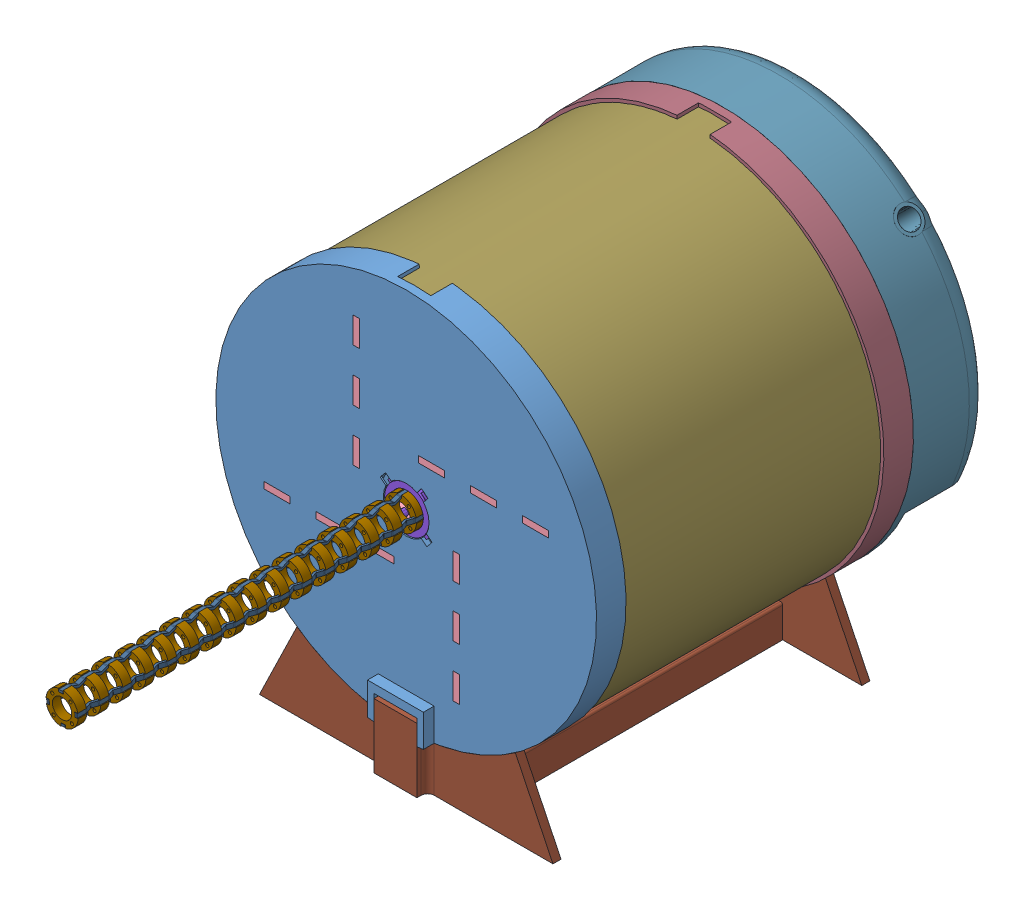
SolidWorks assembly Endo-Continuum-Robot, configuration Default. Lengths in mm.
Overall size (199.74 208.48 344.52).
87 component instances, 16 part files, 24 mates.
Components (placement in the parent):
- FrontCover-1: FrontCover [Default] at (-10.0743 108.611 457.4034) x (0 -1 0) z (0 0 1) size (177.22 177.22 18.75)
- ServoSet-1: ServoSet [Default] at (-169.2832 140.7245 631.1667) x (0 1 0) z (0 0 -1) size (82.84 52.3 148.09)
  - MG996R-Servo-with-Hub-1: MG996R-Servo-with-Hub [Default] at (-42.4416 98.8668 240.9659) x (0 0 -1) z (1 0 0) size (24.11 48.3 54.1)
    - MG996R-Servo-1: MG996R-Servo [Default] at (29.3026 10.0421 49.0781) size (20.3 45.5 54.1)
    - Servo-Hub-1: Servo-Hub [Default] at (29.3026 56.1421 60.3281) x (0.973354 0 0.229307) z (-0.229307 0 0.973354) size (20.05 5.6 20.05)
  - ServoHolderDirect-2: ServoHolderDirect [Default] at (3.7865 137.5089 247.5133) x (-1 0 0) z (0 0 1) size (72.5 3 147.5)
  - MG996R-Servo-with-Hub-4: MG996R-Servo-with-Hub [Default] at (64.7146 98.8668 238.0606) x (0 0 1) z (-1 0 0) size (24.11 48.3 54.1)
    - MG996R-Servo-1: MG996R-Servo [Default] at (29.3026 10.0421 49.0781) size (20.3 45.5 54.1)
    - Servo-Hub-1: Servo-Hub [Default] at (29.3026 56.1421 60.3281) x (0.973354 0 0.229307) z (-0.229307 0 0.973354) size (20.05 5.6 20.05)
  - MG996R-Servo-with-Hub-5: MG996R-Servo-with-Hub [Default] at (53.0146 98.8668 274.0606) x (0 0 1) z (-1 0 0) size (24.11 48.3 54.1)
    - MG996R-Servo-1: MG996R-Servo [Default] at (29.3026 10.0421 49.0781) size (20.3 45.5 54.1)
    - Servo-Hub-1: Servo-Hub [Default] at (29.3026 56.1421 60.3281) x (0.973354 0 0.229307) z (-0.229307 0 0.973354) size (20.05 5.6 20.05)
  - MotorTransmissionMedium-1: MotorTransmissionMedium [Default] at (4.3865 154.2089 267.3633) x (0.973354 0 0.229307) z (0.229307 0 -0.973354) size (44 4 44)
  - MotorTransmissionSmall-1: MotorTransmissionSmall [Default] at (-7.3135 154.2089 303.3633) x (0.973354 0 0.229307) z (0.229307 0 -0.973354) size (24 4 24)
  - MotorTransmissionLarge-1: MotorTransmissionLarge [Default] at (17.8865 154.2089 211.6633) x (-0.973354 0 -0.229307) z (-0.229307 0 0.973354) size (64 4 64)
- ServoSet-3: ServoSet [Default] at (-42.1878 -50.5979 631.1667) x (-1 0 0) z (0 0 -1) size (82.84 52.3 148.09)
  - MG996R-Servo-with-Hub-1: MG996R-Servo-with-Hub [Default] at (-42.4416 98.8668 240.9659) x (0 0 -1) z (1 0 0) size (24.11 48.3 54.1)
    - MG996R-Servo-1: MG996R-Servo [Default] at (29.3026 10.0421 49.0781) size (20.3 45.5 54.1)
    - Servo-Hub-1: Servo-Hub [Default] at (29.3026 56.1421 60.3281) x (0.973354 0 0.229307) z (-0.229307 0 0.973354) size (20.05 5.6 20.05)
  - ServoHolderDirect-2: ServoHolderDirect [Default] at (3.7865 137.5089 247.5133) x (-1 0 0) z (0 0 1) size (72.5 3 147.5)
  - MG996R-Servo-with-Hub-4: MG996R-Servo-with-Hub [Default] at (64.7146 98.8668 238.0606) x (0 0 1) z (-1 0 0) size (24.11 48.3 54.1)
    - MG996R-Servo-1: MG996R-Servo [Default] at (29.3026 10.0421 49.0781) size (20.3 45.5 54.1)
    - Servo-Hub-1: Servo-Hub [Default] at (29.3026 56.1421 60.3281) x (0.973354 0 0.229307) z (-0.229307 0 0.973354) size (20.05 5.6 20.05)
  - MG996R-Servo-with-Hub-5: MG996R-Servo-with-Hub [Default] at (53.0146 98.8668 274.0606) x (0 0 1) z (-1 0 0) size (24.11 48.3 54.1)
    - MG996R-Servo-1: MG996R-Servo [Default] at (29.3026 10.0421 49.0781) size (20.3 45.5 54.1)
    - Servo-Hub-1: Servo-Hub [Default] at (29.3026 56.1421 60.3281) x (0.973354 0 0.229307) z (-0.229307 0 0.973354) size (20.05 5.6 20.05)
  - MotorTransmissionMedium-1: MotorTransmissionMedium [Default] at (4.3865 154.2089 267.3633) x (0.973354 0 0.229307) z (0.229307 0 -0.973354) size (44 4 44)
  - MotorTransmissionSmall-1: MotorTransmissionSmall [Default] at (-7.3135 154.2089 303.3633) x (0.973354 0 0.229307) z (0.229307 0 -0.973354) size (24 4 24)
  - MotorTransmissionLarge-1: MotorTransmissionLarge [Default] at (17.8865 154.2089 211.6633) x (-0.973354 0 -0.229307) z (-0.229307 0 0.973354) size (64 4 64)
- ServoSet-4: ServoSet [Default] at (149.1345 76.4975 631.1667) x (0 -1 0) z (0 0 -1) size (82.84 52.3 148.09)
  - MG996R-Servo-with-Hub-1: MG996R-Servo-with-Hub [Default] at (-42.4416 98.8668 240.9659) x (0 0 -1) z (1 0 0) size (24.11 48.3 54.1)
    - MG996R-Servo-1: MG996R-Servo [Default] at (29.3026 10.0421 49.0781) size (20.3 45.5 54.1)
    - Servo-Hub-1: Servo-Hub [Default] at (29.3026 56.1421 60.3281) x (0.973354 0 0.229307) z (-0.229307 0 0.973354) size (20.05 5.6 20.05)
  - ServoHolderDirect-2: ServoHolderDirect [Default] at (3.7865 137.5089 247.5133) x (-1 0 0) z (0 0 1) size (72.5 3 147.5)
  - MG996R-Servo-with-Hub-4: MG996R-Servo-with-Hub [Default] at (64.7146 98.8668 238.0606) x (0 0 1) z (-1 0 0) size (24.11 48.3 54.1)
    - MG996R-Servo-1: MG996R-Servo [Default] at (29.3026 10.0421 49.0781) size (20.3 45.5 54.1)
    - Servo-Hub-1: Servo-Hub [Default] at (29.3026 56.1421 60.3281) x (0.973354 0 0.229307) z (-0.229307 0 0.973354) size (20.05 5.6 20.05)
  - MG996R-Servo-with-Hub-5: MG996R-Servo-with-Hub [Default] at (53.0146 98.8668 274.0606) x (0 0 1) z (-1 0 0) size (24.11 48.3 54.1)
    - MG996R-Servo-1: MG996R-Servo [Default] at (29.3026 10.0421 49.0781) size (20.3 45.5 54.1)
    - Servo-Hub-1: Servo-Hub [Default] at (29.3026 56.1421 60.3281) x (0.973354 0 0.229307) z (-0.229307 0 0.973354) size (20.05 5.6 20.05)
  - MotorTransmissionMedium-1: MotorTransmissionMedium [Default] at (4.3865 154.2089 267.3633) x (0.973354 0 0.229307) z (0.229307 0 -0.973354) size (44 4 44)
  - MotorTransmissionSmall-1: MotorTransmissionSmall [Default] at (-7.3135 154.2089 303.3633) x (0.973354 0 0.229307) z (0.229307 0 -0.973354) size (24 4 24)
  - MotorTransmissionLarge-1: MotorTransmissionLarge [Default] at (17.8865 154.2089 211.6633) x (-0.973354 0 -0.229307) z (-0.229307 0 0.973354) size (64 4 64)
- ServoSet-5: ServoSet [Default] at (22.0392 267.8199 631.1667) x (1 0 0) z (0 0 -1) size (82.84 52.3 148.09)
  - MG996R-Servo-with-Hub-1: MG996R-Servo-with-Hub [Default] at (-42.4416 98.8668 240.9659) x (0 0 -1) z (1 0 0) size (24.11 48.3 54.1)
    - MG996R-Servo-1: MG996R-Servo [Default] at (29.3026 10.0421 49.0781) size (20.3 45.5 54.1)
    - Servo-Hub-1: Servo-Hub [Default] at (29.3026 56.1421 60.3281) x (0.973354 0 0.229307) z (-0.229307 0 0.973354) size (20.05 5.6 20.05)
  - ServoHolderDirect-2: ServoHolderDirect [Default] at (3.7865 137.5089 247.5133) x (-1 0 0) z (0 0 1) size (72.5 3 147.5)
  - MG996R-Servo-with-Hub-4: MG996R-Servo-with-Hub [Default] at (64.7146 98.8668 238.0606) x (0 0 1) z (-1 0 0) size (24.11 48.3 54.1)
    - MG996R-Servo-1: MG996R-Servo [Default] at (29.3026 10.0421 49.0781) size (20.3 45.5 54.1)
    - Servo-Hub-1: Servo-Hub [Default] at (29.3026 56.1421 60.3281) x (0.973354 0 0.229307) z (-0.229307 0 0.973354) size (20.05 5.6 20.05)
  - MG996R-Servo-with-Hub-5: MG996R-Servo-with-Hub [Default] at (53.0146 98.8668 274.0606) x (0 0 1) z (-1 0 0) size (24.11 48.3 54.1)
    - MG996R-Servo-1: MG996R-Servo [Default] at (29.3026 10.0421 49.0781) size (20.3 45.5 54.1)
    - Servo-Hub-1: Servo-Hub [Default] at (29.3026 56.1421 60.3281) x (0.973354 0 0.229307) z (-0.229307 0 0.973354) size (20.05 5.6 20.05)
  - MotorTransmissionMedium-1: MotorTransmissionMedium [Default] at (4.3865 154.2089 267.3633) x (0.973354 0 0.229307) z (0.229307 0 -0.973354) size (44 4 44)
  - MotorTransmissionSmall-1: MotorTransmissionSmall [Default] at (-7.3135 154.2089 303.3633) x (0.973354 0 0.229307) z (0.229307 0 -0.973354) size (24 4 24)
  - MotorTransmissionLarge-1: MotorTransmissionLarge [Default] at (17.8865 154.2089 211.6633) x (-0.973354 0 -0.229307) z (-0.229307 0 0.973354) size (64 4 64)
- SpineAndLock-1: SpineAndLock [Default] at (8.3738 114.3681 430.6531) x (-0.760407 0.649447 0) z (0 0 1) size (23.7 23.7 163.57)
  - SpineTwistLock-1: SpineTwistLock [Default] at (10.2892 -83.6412 26.4253) size (23.7 23.7 3)
  - Spine3Segments-1: Spine3Segments [Default] at (4.5097 28.4554 36.373) x (-0.707107 -0.707107 0) z (0.707107 -0.707107 0) size (14.85 161.57 14.85)
    - RigidDisc-1: RigidDisc [Default] at (4.4669 6.9477 12.6403) size (14.85 4 14.85)
    - RigidDisc-2: RigidDisc [Default] at (4.4669 -3.5523 12.6403) size (14.85 4 14.85)
    - RigidDisc-3: RigidDisc [Default] at (4.4669 -14.0523 12.6403) size (14.85 4 14.85)
    - RigidDisc-4: RigidDisc [Default] at (4.4669 -24.5523 12.6403) size (14.85 4 14.85)
    - RigidDisc-5: RigidDisc [Default] at (4.4669 -35.0523 12.6403) size (14.85 4 14.85)
    - Ligament-9: Ligament [Default] at (11.0169 10.9477 11.6403) x (0 -1 0) z (-1 0 0) size (161.57 2 2.03)
    - RigidDisc-16: RigidDisc [Default] at (4.4669 -45.5523 12.6403) size (14.85 4 14.85)
    - RigidDisc-17: RigidDisc [Default] at (4.4669 -56.0523 12.6403) size (14.85 4 14.85)
    - RigidDisc-18: RigidDisc [Default] at (4.4669 -66.5523 12.6403) size (14.85 4 14.85)
    - RigidDisc-19: RigidDisc [Default] at (4.4669 -77.0523 12.6403) size (14.85 4 14.85)
    - RigidDisc-20: RigidDisc [Default] at (4.4669 -87.5523 12.6403) size (14.85 4 14.85)
    - RigidDisc-21: RigidDisc [Default] at (4.4669 -98.0523 12.6403) size (14.85 4 14.85)
    - RigidDisc-22: RigidDisc [Default] at (4.4669 -108.5523 12.6403) size (14.85 4 14.85)
    - RigidDisc-23: RigidDisc [Default] at (4.4669 -119.0523 12.6403) size (14.85 4 14.85)
    - RigidDisc-24: RigidDisc [Default] at (4.4669 -129.5523 12.6403) size (14.85 4 14.85)
    - RigidDisc-25: RigidDisc [Default] at (4.4669 -140.0523 12.6403) size (14.85 4 14.85)
    - RigidDisc-26: RigidDisc [Default] at (4.4669 -150.5523 12.6403) size (14.85 4 14.85)
    - Ligament-11: Ligament [Default] at (3.4669 10.9477 6.0903) x (0 -1 0) z (0 0 1) size (161.57 2 2.03)
    - Ligament-12: Ligament [Default] at (-2.0831 10.9477 13.6403) x (0 -1 0) z (1 0 0) size (161.57 2 2.03)
    - Ligament-13: Ligament [Default] at (5.4669 10.9477 19.1903) x (0 -1 0) z (0 0 -1) size (161.57 2 2.03)
- BaseHolder-1: BaseHolder [Default] at (-10.0743 108.611 455.5284) x (0 1 0) z (0 0 -1) size (197.22 177.22 157.5)
- HubCover-1: HubCover [Default] at (-10.0743 108.611 313.6534) x (0.987237 -0.15926 0) z (0 0 1) size (174.22 174.22 140)
- MountAndBack-1: MountAndBack [Default] at (-138.6215 168.0928 198.6011) x (0 -1 0) z (0 0 1) size (177.22 177.22 50.53)
  - BackCover-1: BackCover [Default] at (59.4818 128.5471 115.0523) size (177.22 177.22 18.75)
  - URVMount-1: URVMount [Default] at (59.4818 128.5471 111.3023) x (0 -1 0) z (0 0 1) size (177.22 177.22 36.78)
  - Servo-Driver-1: Servo-Driver [Default] at (43.0849 82.2579 106.3023) x (0 0 1) z (-1 0 0) size (2 25 62.1)
  - Arduino-Uno-1: Arduino-Uno [Default] at (54.6997 184.2196 96.9884) x (0 1 0) z (0 0 -1) size (54 75 15)
Mates (geometry in assembly coordinates):
- Concentric1: concentric aligned: cylinder of FrontCover-1 through (-10.0743 108.611 453.6534) axis (0 0 1) radius 10.65; cylinder of SpineAndLock-1/SpineTwistLock-1 through (-10.0743 108.611 454.0784) axis (0 0 1) radius 10.35
- Concentric2: concentric anti-aligned: cylinder of FrontCover-1 through (-10.0743 108.611 457.4034) axis (0 0 -1) radius 88.611; cylinder of BackHubDirect-1 through (0 106.546 -147.5) axis (0 0 1) radius 88.611
- Concentric13: concentric anti-aligned: cylinder of FrontCover-1 through (-10.0743 108.611 457.4034) axis (0 0 -1) radius 88.611; cylinder of BaseHolder-1 through (-10.0743 108.611 453.6534) axis (0 0 1) radius 88.611
- Coincident16: coincident aligned: plane of FrontCover-1 through (-10.0743 108.611 457.4034) normal (0 0 1); plane of BaseHolder-1 through (-10.0743 108.611 457.4034) normal (0 0 1)
- Parallel1: parallel aligned: plane of FrontCover-1 through (-10.0743 174.761 447.4034) normal (0 -1 0); plane of BaseHolder-1 through (-78.3995 0 453.6534) normal (0 -1 0)
- Tangent2: tangent anti-aligned: face of BackHubDirect-1; plane of BackHubDirect-1 through (56 136.046 -160.5) normal (0 0 -1)
- Coincident17: coincident anti-aligned: plane of BackHubDirect-1 through (0 106.546 -150.5) normal (0 0 -1); plane of ServoDriverDirect-1 through (-35.2892 152.4928 -150.5) normal (0 0 1)
- Concentric16: concentric anti-aligned: cylinder of BackHubDirect-1 through (0 106.546 -147.5) axis (0 0 1) radius 88.611; cylinder of HubCover-1 through (-10.0743 108.611 453.6534) axis (0 0 -1) radius 87.111
- Coincident18: coincident anti-aligned: plane of FrontCover-1 through (-10.0743 108.611 453.6534) normal (0 0 -1); circle of HubCover-1
- Coincident19: coincident anti-aligned: plane of FrontCover-1 through (-31.7743 114.261 447.4034) normal (0 1 0); plane of ServoSet-1/ServoHolderDirect-2 through (-34.7743 114.261 383.6534) normal (0 -1 0)
- Coincident20: coincident anti-aligned: plane of FrontCover-1 through (-31.7743 114.261 447.4034) normal (-1 0 0); plane of ServoSet-1/ServoHolderDirect-2 through (-31.7743 144.511 383.6534) normal (1 0 0)
- Coincident21: coincident aligned: plane of FrontCover-1 through (-10.0743 108.611 457.4034) normal (0 0 1); plane of ServoSet-1/ServoHolderDirect-2 through (-34.7743 144.511 457.4034) normal (0 0 1)
- Coincident22: coincident aligned: plane of ServoSet-1/ServoHolderDirect-2 through (-34.7743 144.511 309.9034) normal (0 0 -1); plane of BackHubDirect-1 through (0 106.546 -147.5) normal (0 0 -1)
- Coincident23: coincident anti-aligned: plane of ServoSet-1/ServoHolderDirect-2 through (-34.7743 144.511 383.6534) normal (-1 0 0); plane of BackHubDirect-1 through (-24.7 106.546 -153.75) normal (1 0 0)
- Tangent7: tangent anti-aligned: cylinder of ? through (56 136.046 -160.5) axis (0 0 1) radius 1.5; edge_curve of ?
- Tangent8: tangent anti-aligned: cylinder of ? through (25 136.046 -160.5) axis (0 0 1) radius 1.5; edge_curve of ?
- Concentric17: concentric anti-aligned: cylinder of BackHubDirect-1 through (-36.3499 151.4322 -150.5) axis (0 0 1) radius 0.75; cylinder of ServoDriverDirect-1 through (-36.3499 151.4322 -150.5) axis (0 0 -1) radius 1
- Concentric18: concentric anti-aligned: cylinder of BackHubDirect-1 through (-56.2286 151.4322 -150.5) axis (0 0 1) radius 0.75; cylinder of ServoDriverDirect-1 through (-56.2286 151.4322 -150.5) axis (0 0 -1) radius 1
- Coincident24: coincident anti-aligned: plane of BaseHolder-1 through (-78.3995 0 453.6534) normal (0 -1 0)
- Concentric19: concentric anti-aligned: cylinder of FrontCover-1 through (-10.0743 108.611 457.4034) axis (0 0 -1) radius 88.611; cylinder of MountAndBack-1/BackCover-1 through (-10.0743 108.611 309.9034) axis (0 0 1) radius 88.611
- Coincident27: coincident aligned: plane of FrontCover-1 through (-2.3514 196.8848 443.6534) normal (-0.996195 0.087156 0); plane of MountAndBack-1/BackCover-1 through (-2.3514 196.8848 323.6534) normal (-0.996195 0.087156 0)
- Coincident28: coincident aligned: plane of ServoSet-1/ServoHolderDirect-2 through (-34.7743 144.511 309.9034) normal (0 0 -1); plane of MountAndBack-1/BackCover-1 through (-10.0743 108.611 309.9034) normal (0 0 -1)
- Concentric20: concentric aligned: cylinder of FrontCover-1 through (-10.0743 108.611 457.4034) axis (0 0 -1) radius 88.611; cylinder of HubCover-1 through (-10.0743 108.611 453.6534) axis (0 0 -1) radius 87.111
- Coincident29: coincident anti-aligned: plane of FrontCover-1 through (-10.0743 108.611 455.0784) normal (0 0 1); plane of SpineAndLock-1/SpineTwistLock-1 through (-3.2431 114.4151 455.0784) normal (0 0 -1)
